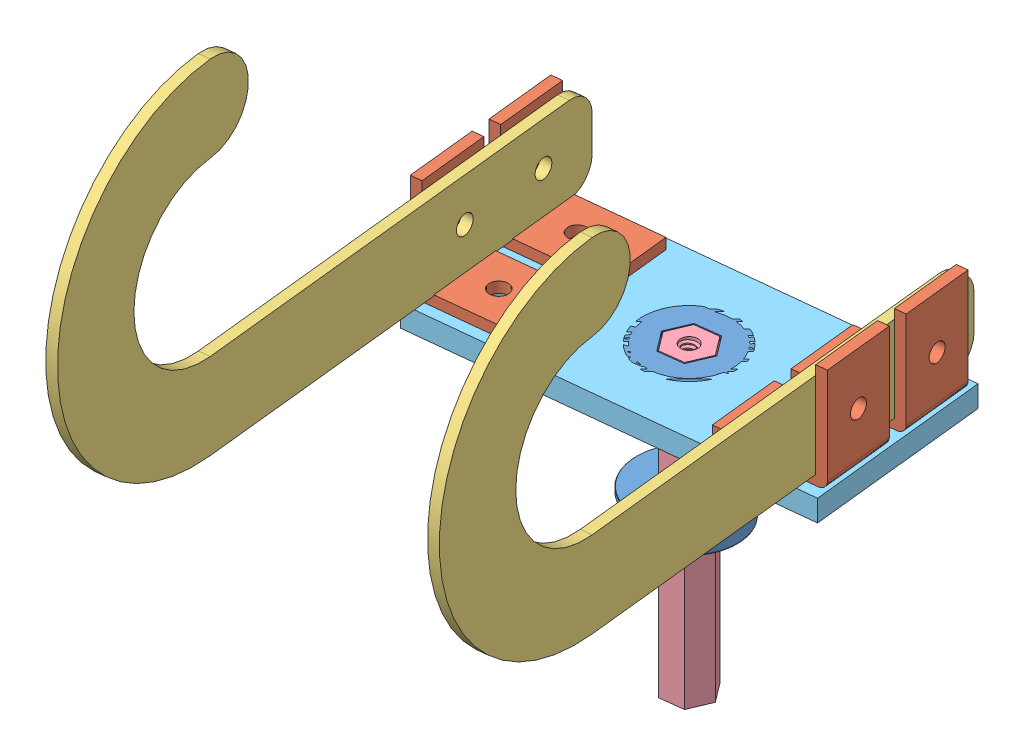
SolidWorks assembly climber no arm, configuration Default. Lengths in mm.
Overall size (126.86 194.27 187.93).
10 component instances, 5 part files, 21 mates.
Components (placement in the parent):
- half in hex bearing for clibmer-1: half in hex bearing for clibmer [Default] at (1516.0789 990.308 1577.6097) x (0.992268 0 -0.124114) z (0 -1 0) size (31.12 31.12 7.93)
- Bracket for climber prototype-3: Bracket for climber prototype [Default] at (1478.1134 991.8955 1605.1105) x (-0.994487 0 0.104862) z (-0.104862 0 -0.994487) size (30.99 30.99 20.57)
- Bracket for climber prototype-4: Bracket for climber prototype [Default] at (1554.0444 991.8955 1550.1089) x (0.994487 0 -0.104862) z (0.104862 0 0.994487) size (30.99 30.99 20.57)
- Bracket for climber prototype-5: Bracket for climber prototype [Default] at (1475.37 991.8955 1579.0927) x (-0.994487 0 0.104862) z (-0.104862 0 -0.994487) size (30.99 30.99 20.57)
- Bracket for climber prototype-6: Bracket for climber prototype [Default] at (1556.7878 991.8955 1576.1267) x (0.994487 0 -0.104862) z (0.104862 0 0.994487) size (30.99 30.99 20.57)
- Candy cane claw-1: Candy cane claw [Default] at (1463.4973 1010.6048 1553.6954) x (0 -1 0) z (-0.994487 0 0.104862) size (101.6 177.8 3.17)
- Candy cane claw-2: Candy cane claw [Default] at (1565.6739 1010.6048 1542.9215) x (0 -1 0) z (-0.994487 0 0.104862) size (101.6 177.8 3.17)
- Hex shaft for climber-1: Hex shaft for climber [Default] at (1516.0789 914.108 1577.6097) x (0 1 0) z (0.992268 0 -0.124114) size (89.82 12 13.86)
- half in hex bearing for clibmer-2: half in hex bearing for clibmer [Default] at (1516.0789 945.858 1577.6097) x (-0.166109 0 -0.986107) z (0 1 0) size (31.12 31.12 7.93)
- wood piece for pivot in climber-1: wood piece for pivot in climber [Default] at (1516.0789 983.958 1577.6097) x (0 1 0) z (-0.994487 0 0.104862) size (6.35 53.34 112.27)
Mates (geometry in assembly coordinates):
- Concentric12: concentric anti-aligned: cylinder of Bracket for climber prototype-5 through (1489.6998 1005.802 1567.2377) axis (-0.994487 0 0.104862) radius 2.667; cylinder of Candy cane claw-1 through (1462.0402 1005.802 1570.1542) axis (0.994487 0 -0.104862) radius 2.794
- Parallel10: parallel anti-aligned: cylinder of Bracket for climber prototype-3 through (1492.4432 1005.802 1593.2554) axis (-0.994487 0 0.104862) radius 2.667; cylinder of Candy cane claw-1 through (1464.7836 1005.802 1596.172) axis (0.994487 0 -0.104862) radius 2.794
- Coincident15: coincident anti-aligned: plane of Bracket for climber prototype-3 through (1463.7048 993.483 1585.9417) normal (0.994487 0 -0.104862); plane of Candy cane claw-1 through (1473.6573 1043.9604 1680.3281) normal (-0.994487 0 0.104862)
- Concentric14: concentric anti-aligned: cylinder of Bracket for climber prototype-3 through (1492.4432 1005.802 1593.2554) axis (-0.994487 0 0.104862) radius 2.667; cylinder of Candy cane claw-1 through (1464.7836 1005.802 1596.172) axis (0.994487 0 -0.104862) radius 2.794
- Concentric15: concentric aligned: cylinder of Bracket for climber prototype-6 through (1542.458 1005.802 1587.9817) axis (0.994487 0 -0.104862) radius 2.667; cylinder of Candy cane claw-2 through (1566.9601 1005.802 1585.3981) axis (0.994487 0 -0.104862) radius 2.794
- Concentric16: concentric aligned: cylinder of Bracket for climber prototype-4 through (1539.7146 1005.802 1561.964) axis (0.994487 0 -0.104862) radius 2.667; cylinder of Candy cane claw-2 through (1564.2167 1005.802 1559.3804) axis (0.994487 0 -0.104862) radius 2.794
- Coincident16: coincident anti-aligned: plane of Bracket for climber prototype-6 through (1571.1963 993.483 1595.2955) normal (-0.994487 0 0.104862); plane of Candy cane claw-2 through (1578.9913 1043.9604 1669.2214) normal (0.994487 0 -0.104862)
- Concentric18: concentric aligned: circle of Hex shaft for climber-1; circle of wood piece for pivot in climber-1
- Coincident23: coincident aligned: plane of Hex shaft for climber-1 through (1516.0789 990.308 1577.6097) normal (0 1 0); plane of wood piece for pivot in climber-1 through (1516.0789 990.308 1577.6097) normal (0 1 0)
- Concentric21: concentric aligned: circle of half in hex bearing for clibmer-1; circle of Hex shaft for climber-1
- Coincident32: coincident aligned: plane of half in hex bearing for clibmer-1 through (1516.0789 990.308 1577.6097) normal (0 1 0); plane of wood piece for pivot in climber-1 through (1516.0789 990.308 1577.6097) normal (0 1 0)
- Parallel15: parallel anti-aligned: line of Bracket for climber prototype-3 through (1491.3645 990.308 1583.0252) axis (-0.994487 0 0.104862); line of Bracket for climber prototype-6 through (1541.3792 990.308 1577.7514) axis (0.994487 0 -0.104862)
- Parallel16: parallel anti-aligned: line of Bracket for climber prototype-4 through (1540.7933 990.308 1572.1942) axis (0.994487 0 -0.104862); line of Bracket for climber prototype-5 through (1490.7785 990.308 1577.468) axis (-0.994487 0 0.104862)
- Coincident38: coincident anti-aligned: plane of Bracket for climber prototype-5 through (1460.9615 993.483 1559.9239) normal (0.994487 0 -0.104862); plane of Candy cane claw-1 through (1473.6573 1043.9604 1680.3281) normal (-0.994487 0 0.104862)
- Concentric23: concentric aligned: cylinder of Bracket for climber prototype-3 through (1477.0346 1021.296 1594.8802) axis (0 -1 0) radius 2.794; cylinder of wood piece for pivot in climber-1 through (1477.0346 990.308 1594.8802) axis (0 -1 0) radius 3.175
- Concentric24: concentric aligned: cylinder of Bracket for climber prototype-5 through (1474.2912 1021.296 1568.8624) axis (0 -1 0) radius 2.794; cylinder of wood piece for pivot in climber-1 through (1474.2912 990.308 1568.8624) axis (0 -1 0) radius 3.175
- Concentric25: concentric aligned: cylinder of Bracket for climber prototype-6 through (1557.8665 1021.296 1586.357) axis (0 -1 0) radius 2.794; cylinder of wood piece for pivot in climber-1 through (1557.8665 990.308 1586.357) axis (0 -1 0) radius 3.175
- Concentric26: concentric aligned: cylinder of Bracket for climber prototype-4 through (1555.1231 1021.296 1560.3392) axis (0 -1 0) radius 2.794; cylinder of wood piece for pivot in climber-1 through (1555.1231 990.308 1560.3392) axis (0 -1 0) radius 3.175
- Coincident40: coincident anti-aligned: plane of Bracket for climber prototype-6 through (1574.3538 990.308 1594.9626) normal (0 -1 0); plane of wood piece for pivot in climber-1 through (1516.0789 990.308 1577.6097) normal (0 1 0)
- Coincident41: coincident anti-aligned: plane of Bracket for climber prototype-3 through (1460.5474 990.308 1586.2746) normal (0 -1 0); plane of wood piece for pivot in climber-1 through (1516.0789 990.308 1577.6097) normal (0 1 0)
- Parallel18: parallel anti-aligned: plane of half in hex bearing for clibmer-1 through (1508.8032 982.3806 1578.5197) normal (0.797272 0 -0.60362); plane of Hex shaft for climber-1 through (1509.2043 901.408 1578.4696) normal (-0.797272 0 0.60362)
